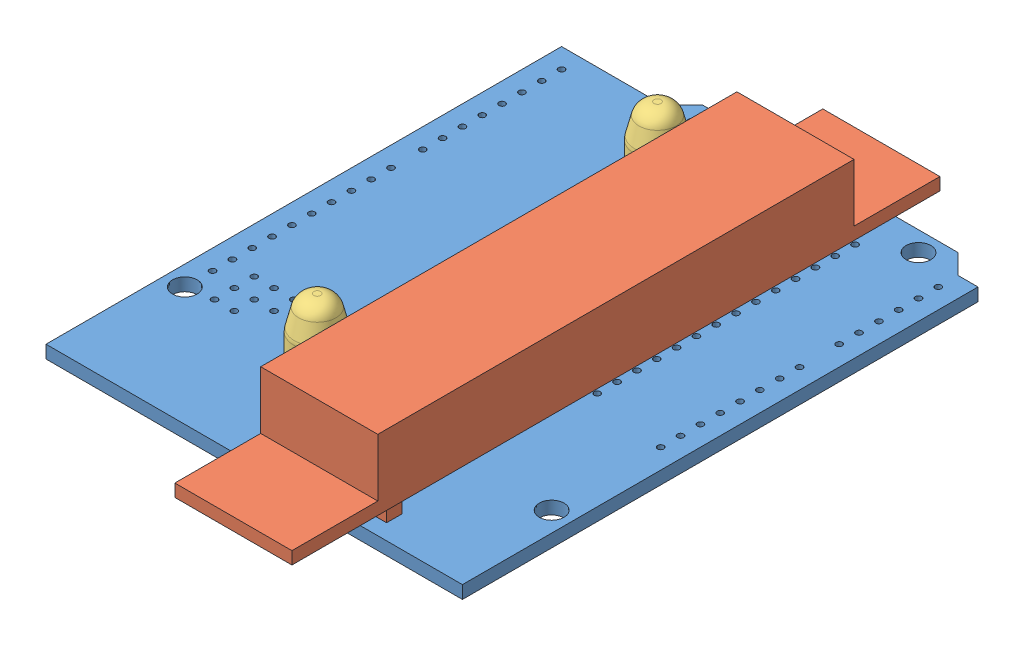
SolidWorks assembly LR_RECV_hat, configuration Default. Lengths in mm.
Overall size (53.34 12.9 83).
4 component instances, 3 part files, 15 mates.
Components (placement in the parent):
- UNO board-1: UNO board [Default] at origin size (53.34 1.65 68.58)
- LR_MAX7219_display-1: LR_MAX7219_display [Default] at (-18.34 2.25 -30.5) x (0 0 -1) z (1 0 0) size (83 11.25 15)
- LED-1: LED [Default] at (-32.09 0 -57.08) size (6 9 6)
- LED-2: LED [Default] at (-32.59 0 -14) size (6 9 6)
Mates (geometry in assembly coordinates):
- Coincident1: coincident aligned: plane of UNO board-1 through (0 0 0) normal (0 0 1); plane of assembly
- Coincident2: coincident aligned: plane of UNO board-1 through (0 0 0) normal (0 1 0); plane of assembly
- Coincident3: coincident aligned: plane of UNO board-1 through (0 0 0) normal (1 0 0); plane of assembly
- Coincident4: coincident anti-aligned: plane of UNO board-1 through (0 0 0) normal (0 1 0); plane of LR_MAX7219_display-1 through (-18.34 0 -30.5) normal (0 -1 0)
- Parallel1: parallel anti-aligned: plane of UNO board-1 through (-53.34 0 0) normal (-1 0 0); plane of LR_MAX7219_display-1 through (-10.84 3.85 11) normal (1 0 0)
- Distance1: distance = 27.5 mm aligned: plane of LR_MAX7219_display-1 through (-25.84 3.85 11) normal (-1 0 0); plane of UNO board-1 through (-53.34 0 0) normal (-1 0 0)
- Coincident5: coincident aligned: plane of UNO board-1 through (0 0 0) normal (0 0 1); plane of LR_MAX7219_display-1 through (-10.84 11.25 0) normal (0 0 1)
- Coincident6: coincident aligned: plane of UNO board-1 through (0 0 0) normal (0 1 0); circle of LED-1
- Distance3: distance = 21.25 mm: point of LED-1; plane of UNO board-1 through (-53.34 0 0) normal (-1 0 0)
- Distance4: distance = 11.5 mm: point of LED-1; plane of UNO board-1 through (-37.846 0 -68.58) normal (0 0 -1)
- Parallel2: parallel anti-aligned: plane of UNO board-1 through (-53.34 0 0) normal (-1 0 0); plane of LED-1 through (-32.09 0 -57.08) normal (1 0 0)
- Coincident7: coincident: plane of UNO board-1 through (0 0 0) normal (0 1 0); plane of LED-2 through (-32.59 0 -14) normal (0 -1 0)
- Distance5: distance = 14 mm: point of LED-2; plane of UNO board-1 through (0 0 0) normal (0 0 1)
- Distance7: distance = 20.75 mm: point of LED-2; plane of UNO board-1 through (-53.34 0 0) normal (-1 0 0)
- Parallel3: parallel aligned: plane of UNO board-1 through (0 0 0) normal (0 0 1); plane of LED-2 through (-32.59 0 -14) normal (0 0 1)
